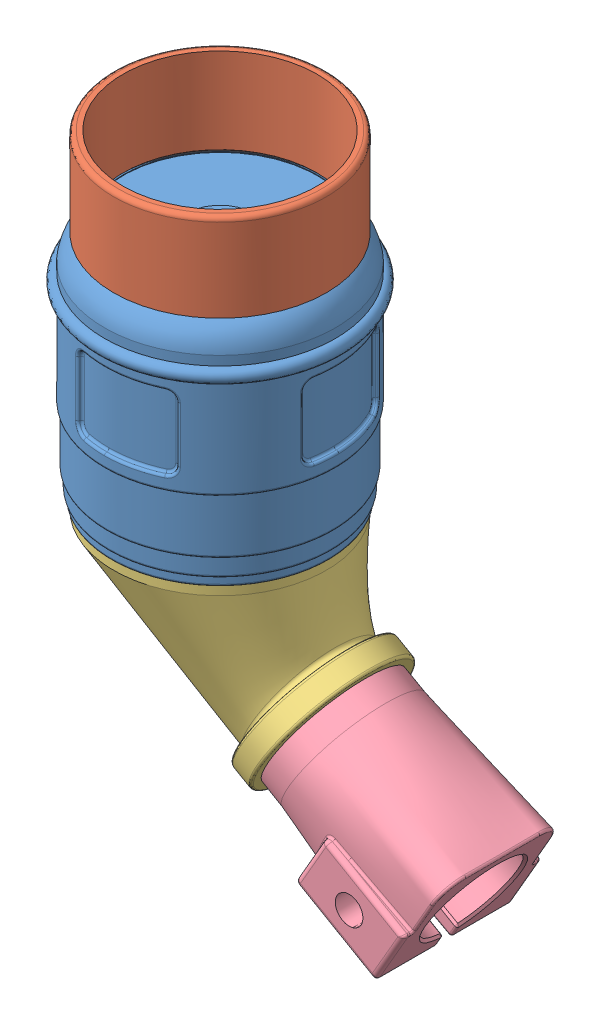
SolidWorks assembly Base, configuration Default. Lengths in mm.
Overall size (87.72 129.75 53.06).
4 component instances, 4 part files, 2 mates.
Components (placement in the parent):
- Manicotto Verde neroSLDPRT-1: Manicotto Verde neroSLDPRT [Default] at (6.647 41.4343 38.3288) size (53.06 50.12 53.06)
- Manicotto arancione-1: Manicotto arancione [Default] at (6.647 41.4343 38.3288) size (46 19 46)
- Part3^Base-1: Part3^Base [Default] at (0 -8.5657 0) x (-1 0 0) z (0 -1 0) size (55.66 47.93 44.56) (virtual)
- Part4^Base-1: Part4^Base [Default] at (39.8712 -23.0197 0) x (0 0 -1) z (0.866025 -0.5 0) size (30 28.56 40) (virtual)
Mates (geometry in assembly coordinates):
- Tangent2: tangent: plane of Manicotto Verde neroSLDPRT-1 through (6.647 41.4343 38.3288) normal (0 1 0); circle of Manicotto arancione-1
- Concentric2: concentric anti-aligned: circle of Manicotto Verde neroSLDPRT-1; circle of Manicotto arancione-1
